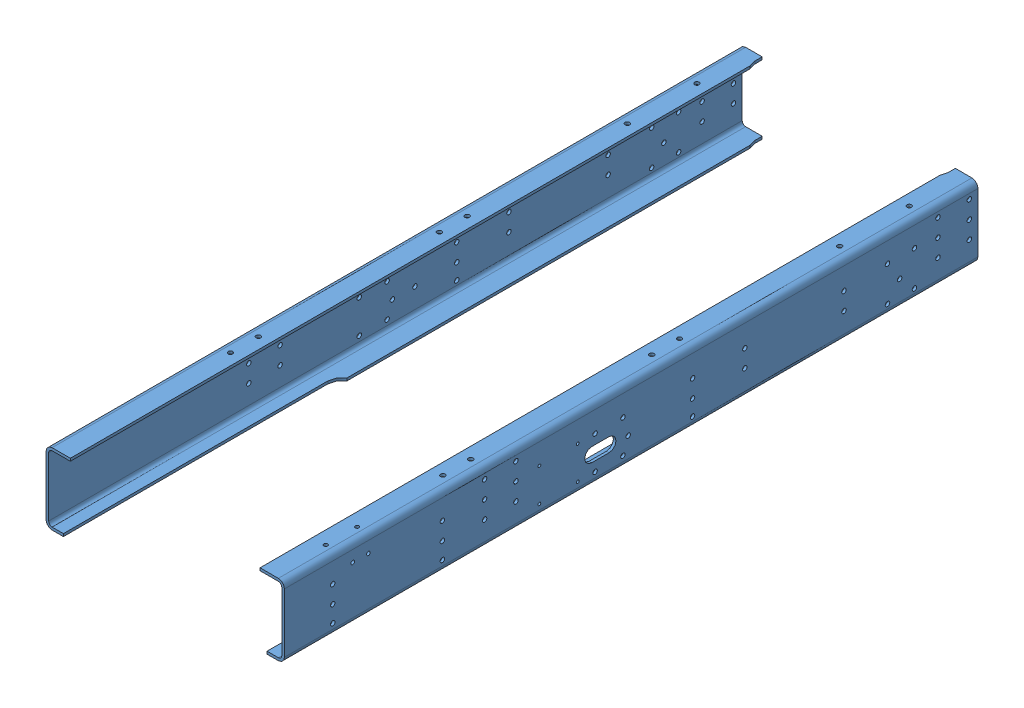
SolidWorks assembly 4129-CC1, configuration Both Rails. Lengths in mm.
Overall size (869.95 260.35 2530.47).
2 component instances, 1 part files, 6 mates.
Components (placement in the parent):
- 1982-CC1-1: 1982-CC1 [1982-CC1-100] at (434.975 0 1844.675) size (88.9 260.35 2530.47)
- 1982-CC1-2: 1982-CC1 [1982-CC1-100] at (-434.975 0 -685.8) x (-1 0 0) z (0 0 -1) size (88.9 260.35 2530.47)
Mates (geometry in assembly coordinates):
- Coincident1: coincident aligned: plane of ?; plane of assembly
- Coincident2: coincident aligned: plane of ?; plane of assembly
- Coincident3: coincident aligned: plane of ?; plane of assembly
- Coincident4: coincident anti-aligned: plane of ?; plane of assembly
- Coincident5: coincident anti-aligned: plane of ?; plane of assembly
- Coincident6: coincident aligned: 
